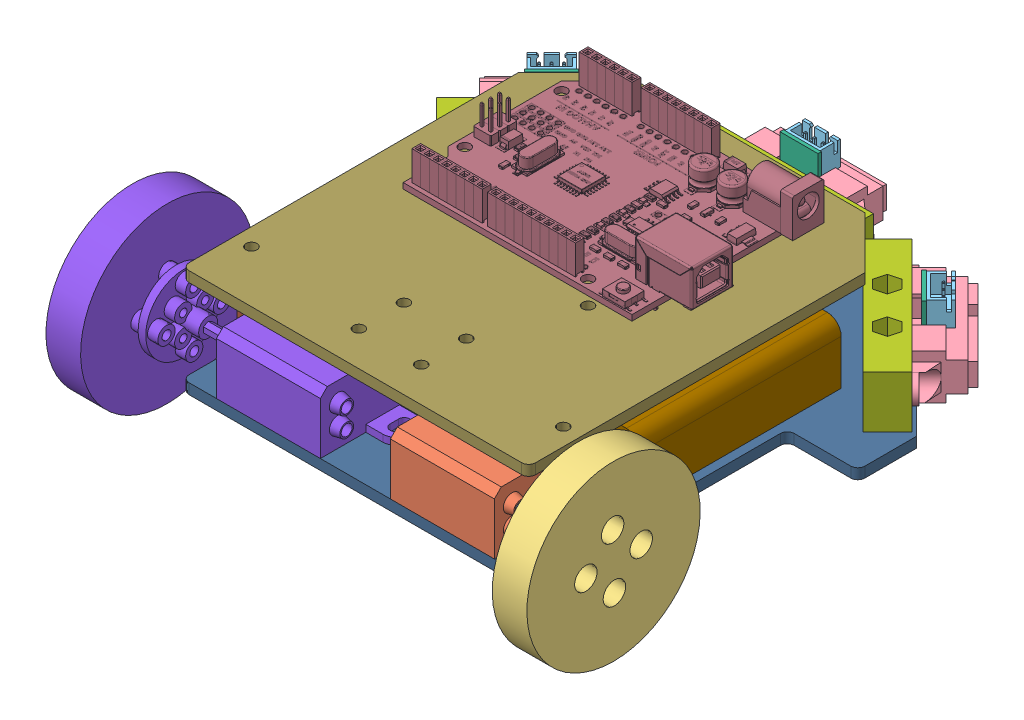
SolidWorks assembly Assembly, configuration ﾃﾞﾌｫﾙﾄ. Lengths in mm.
Overall size (156.27 59.92 160.17).
29 component instances, 13 part files, 0 mates.
Components (placement in the parent):
- Assembly.stp-1: Assembly.stp [ﾃﾞﾌｫﾙﾄ] at origin size (156.27 59.92 160.17)
  - tamiya-12-speed-gearbox.stp-1: tamiya-12-speed-gearbox.stp [ﾃﾞﾌｫﾙﾄ] at (-78.4751 -83.7315 -49.9876) x (-1 0 0) z (0 1 0) size (67.9 51.87 51.55)
    - crank-plate.stp-1: crank-plate.stp [ﾃﾞﾌｫﾙﾄ] at (-29.5 26.1 11.5) x (0 0 -1) z (-1 0 0) size (22 22 31.8)
    - Part4.stp-1: Part4.stp [ﾃﾞﾌｫﾙﾄ] at origin size (47.2 31.2 17)
    - tire.stp-1: tire.stp [ﾃﾞﾌｫﾙﾄ] at (-34.3 26.1 11.5) x (-1 0 0) z (0 -0.031448 -0.999505) size (10 50 50)
  - IR Sharp sensor.stp-1: IR Sharp sensor.stp [ﾃﾞﾌｫﾙﾄ] at (-145.2993 -74.5194 -153.0265) x (0 1 0) z (-1 0 0) size (20 23.5 47)
    - Sharp GP2Y.stp-1: Sharp GP2Y.stp [ﾃﾞﾌｫﾙﾄ] at (-1.7121 -8.2388 -41.7242) x (0 1 0) z (0 0 -1) size (13.5 13 44.5)
    - Header 3-pin.stp-1: Header 3-pin.stp [ﾃﾞﾌｫﾙﾄ] at (3.7879 -2.2888 -41.7242) x (0 0 1) z (0 1 0) size (10.16 7.2 5.9)
    - PCB.stp-1: PCB.stp [ﾃﾞﾌｫﾙﾄ] at (10.7879 -5.2388 -41.7242) x (0 0 1) z (0 -1 0) size (27.5 18 1)
    - Part1.stp-1: Part1.stp [ﾃﾞﾌｫﾙﾄ] at (-9.2121 -18.2388 -65.2242) x (0 0 1) z (-1 0 0) size (47 10 15)
  - IR Sharp sensor.stp-2: IR Sharp sensor.stp [ﾃﾞﾌｫﾙﾄ] at (-190.8749 -74.5194 -103.7251) x (0 1 0) z (-0.707107 0 0.707107) size (20 23.5 47)
    - Sharp GP2Y.stp-1: Sharp GP2Y.stp [ﾃﾞﾌｫﾙﾄ] at (-1.7121 -8.2388 -41.7242) x (0 1 0) z (0 0 -1) size (13.5 13 44.5)
    - Header 3-pin.stp-1: Header 3-pin.stp [ﾃﾞﾌｫﾙﾄ] at (3.7879 -2.2888 -41.7242) x (0 0 1) z (0 1 0) size (10.16 7.2 5.9)
    - PCB.stp-1: PCB.stp [ﾃﾞﾌｫﾙﾄ] at (10.7879 -5.2388 -41.7242) x (0 0 1) z (0 -1 0) size (27.5 18 1)
    - Part1.stp-1: Part1.stp [ﾃﾞﾌｫﾙﾄ] at (-9.2121 -18.2388 -65.2242) x (0 0 1) z (-1 0 0) size (47 10 15)
  - IR Sharp sensor.stp-3: IR Sharp sensor.stp [ﾃﾞﾌｫﾙﾄ] at (-75.2823 -74.5194 -162.7321) x (0 1 0) z (-0.707107 0 -0.707107) size (20 23.5 47)
    - Sharp GP2Y.stp-1: Sharp GP2Y.stp [ﾃﾞﾌｫﾙﾄ] at (-1.7121 -8.2388 -41.7242) x (0 1 0) z (0 0 -1) size (13.5 13 44.5)
    - Header 3-pin.stp-1: Header 3-pin.stp [ﾃﾞﾌｫﾙﾄ] at (3.7879 -2.2888 -41.7242) x (0 0 1) z (0 1 0) size (10.16 7.2 5.9)
    - PCB.stp-1: PCB.stp [ﾃﾞﾌｫﾙﾄ] at (10.7879 -5.2388 -41.7242) x (0 0 1) z (0 -1 0) size (27.5 18 1)
    - Part1.stp-1: Part1.stp [ﾃﾞﾌｫﾙﾄ] at (-9.2121 -18.2388 -65.2242) x (0 0 1) z (-1 0 0) size (47 10 15)
  - Part14.stp-1: Part14.stp [ﾃﾞﾌｫﾙﾄ] at (-128.6751 -83.7315 -49.9876) x (-1 0 0) z (0 1 0) size (67.9 51.1 50)
  - cellcase.stp-1: cellcase.stp [ﾃﾞﾌｫﾙﾄ] at (-56.0751 -83.7315 -53.4876) size (47 17 58)
  - cellcase.stp-2: cellcase.stp [ﾃﾞﾌｫﾙﾄ] at (-104.0751 -83.7315 -53.4876) size (47 17 58)
  - frame.stp-1: frame.stp [ﾃﾞﾌｫﾙﾄ] at (-153.5751 -86.7315 -18.7876) size (140.71 3 127)
  - spacer.stp-1: spacer.stp [ﾃﾞﾌｫﾙﾄ] at (-103.5751 -83.7315 -120.7876) x (0.928415 0 0.371546) z (-0.371546 0 0.928415) size (6 25 6)
  - spacer.stp-2: spacer.stp [ﾃﾞﾌｫﾙﾄ] at (-58.5751 -83.7315 -33.7876) x (0.009399 0 -0.999956) z (0.999956 0 0.009399) size (6 25 6)
  - spacer.stp-3: spacer.stp [ﾃﾞﾌｫﾙﾄ] at (-148.5751 -83.7315 -33.7876) x (0.480286 0 -0.877112) z (0.877112 0 0.480286) size (6 25 6)
  - frame2.stp-1: frame2.stp [ﾃﾞﾌｫﾙﾄ] at (-153.5751 -58.7315 -18.7876) size (100 3 112)
  - ArduinoUno.stp-1: ArduinoUno.stp [ﾃﾞﾌｫﾙﾄ] at (-104.3256 -50.7315 -91.7379) size (76.33 15.58 53.34)
